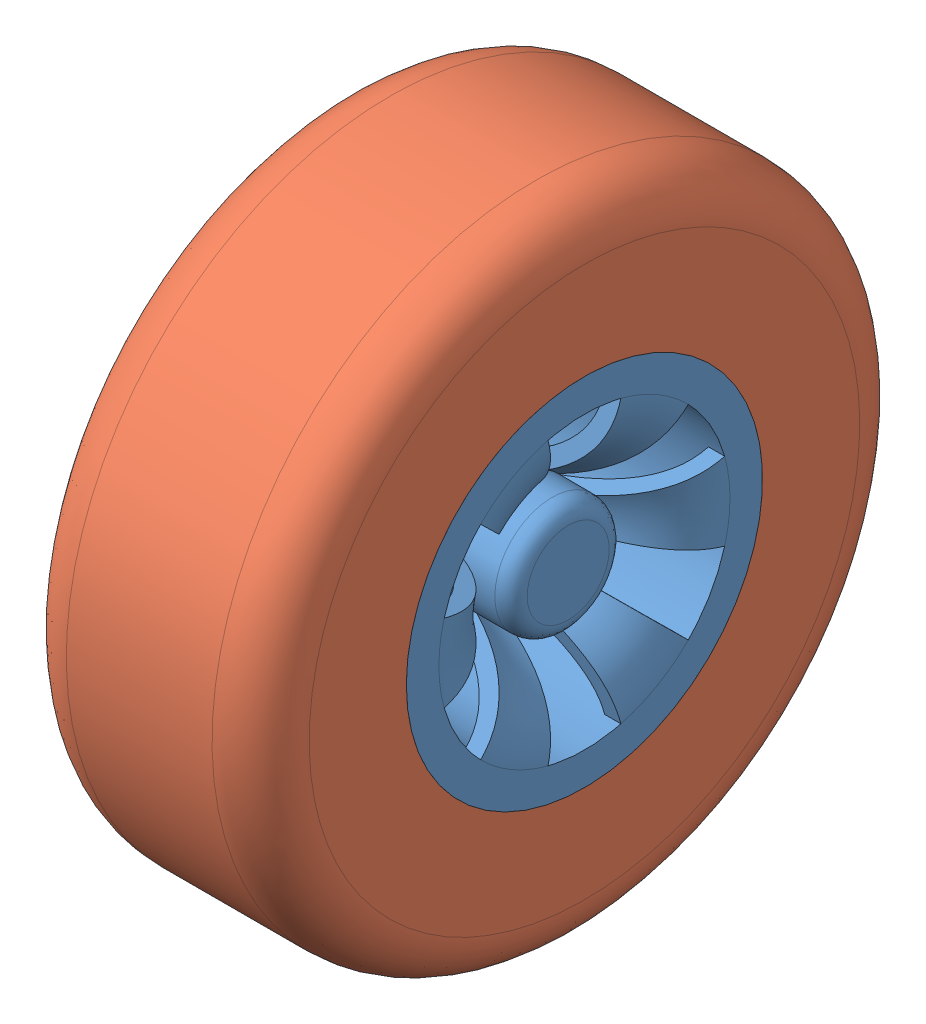
SolidWorks assembly Aries project wheel, configuration Default. Lengths in mm.
Overall size (15 45.35 45.35).
2 component instances, 2 part files, 1 mates.
Components (placement in the parent):
- Aries Project rim-1: Aries Project rim [Default] at (-2.2797 14.8361 20.1437) size (14 22 22)
- Aries poject wheel ext-1: Aries poject wheel ext [Default] at (4.7228 14.8361 20.1437) x (0 0.144321 0.989531) z (-1 0 0) size (40 40 15)
Mates (geometry in assembly coordinates):
- Coincident1: coincident anti-aligned: circle of Aries Project rim-1; plane of Aries poject wheel ext-1 through (4.7228 14.8361 20.1437) normal (1 0 0)
